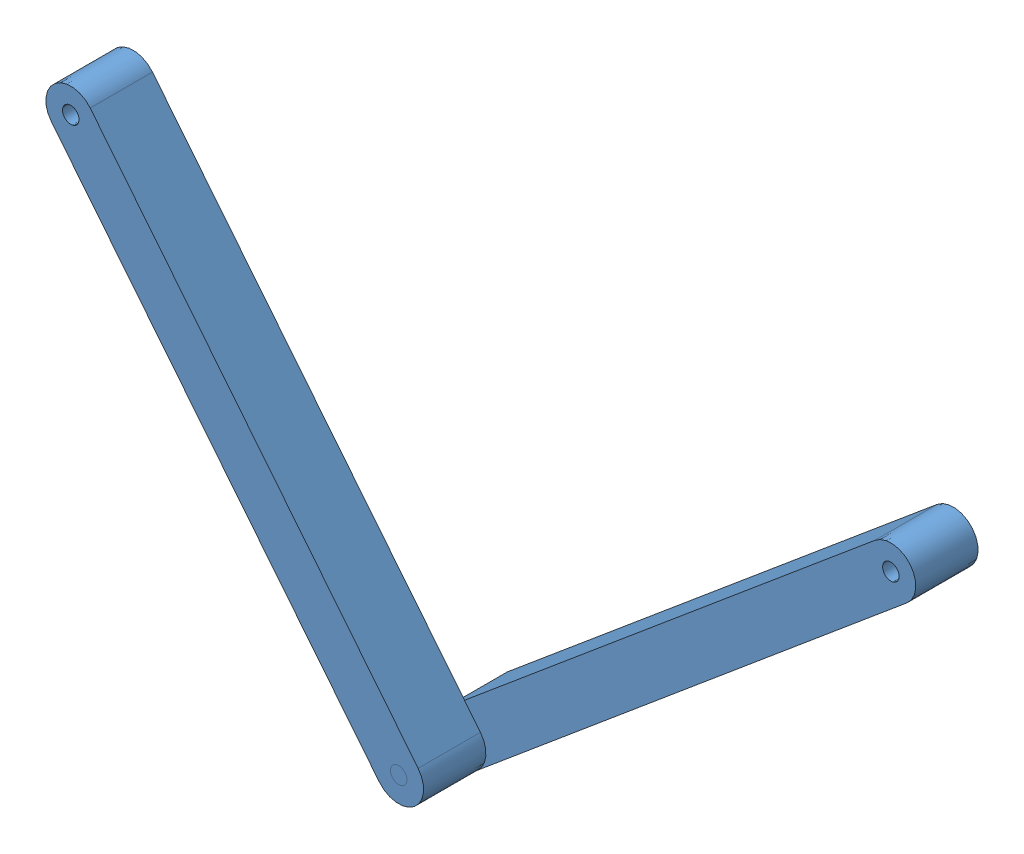
SolidWorks assembly Brazo, configuration Default. Lengths in mm.
Overall size (65.63 38.74 10).
3 component instances, 1 part files, 4 mates.
Components (placement in the parent):
- Brazo_Piezas-1: Brazo_Piezas [Eslabon C] at (-23.6944 12.2459 20.8856) size (38.5 32.89 5)
- Brazo_Piezas-2: Brazo_Piezas [Eslabon B] at (-58.6612 40.1721 25.8856) x (0.620775 -0.783989 0) z (0 0 1) size (46 4.31 5)
- Brazo_Piezas-3: Brazo_Piezas [PIN2] at (5.2564 -20.3806 25.8856) x (0.781211 0.624268 0) z (0 0 1) size (1.33 1.33 10)
Mates (geometry in assembly coordinates):
- Concéntrica1: concentric aligned: circle of Brazo_Piezas-1; circle of Brazo_Piezas-2
- Coincidente2: coincident anti-aligned: plane of Brazo_Piezas-1 through (0.3056 12.2459 25.8856) normal (0 0 1); plane of Brazo_Piezas-2 through (-26.0129 44.9773 25.8856) normal (0 0 -1)
- Concéntrica2: concentric aligned: circle of Brazo_Piezas-2; circle of Brazo_Piezas-3
- Coincidente4: coincident aligned: plane of Brazo_Piezas-2 through (-26.0129 44.9773 30.8856) normal (0 0 1); plane of Brazo_Piezas-3 through (0.3056 12.2459 30.8856) normal (0 0 1)
